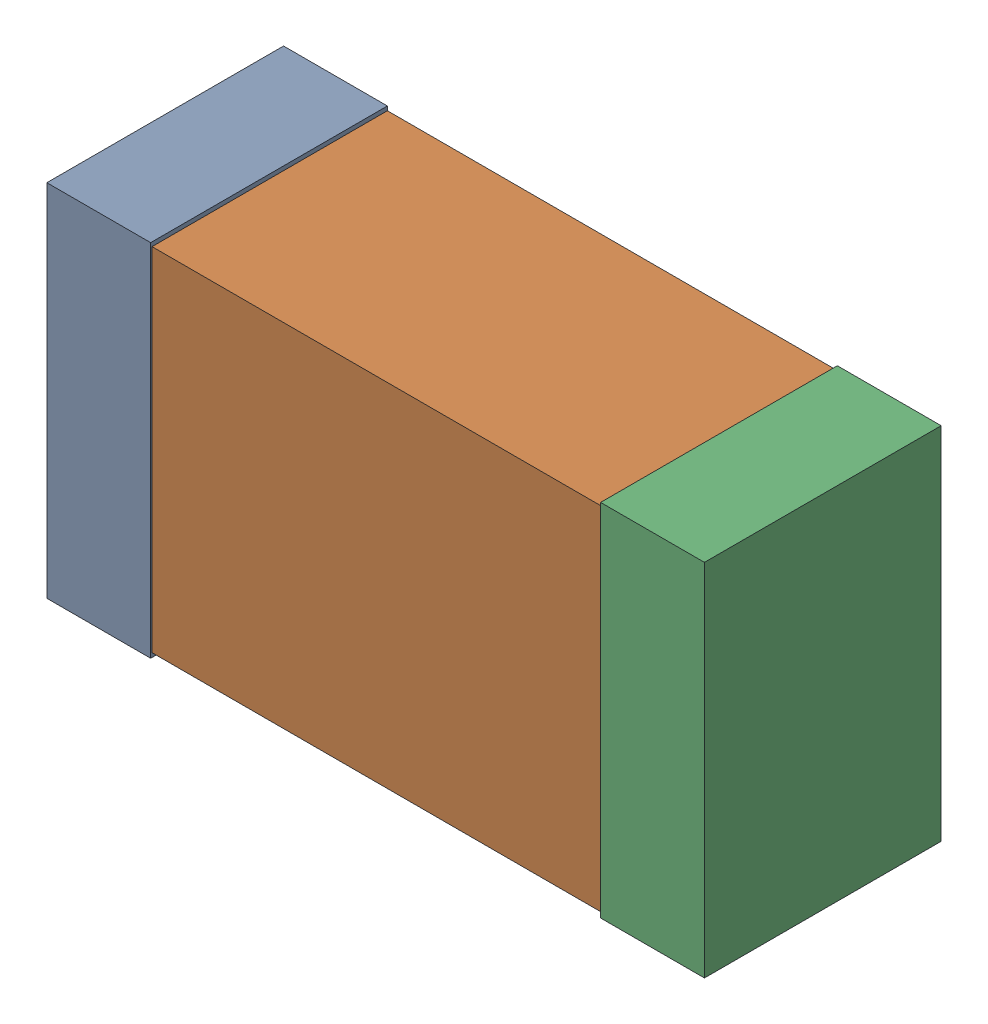
SolidWorks assembly C9_Motor_4Kanaloa_v2.0.0_Motor, configuration Default. Lengths in mm.
Overall size (2.38 1.3 0.85).
6 component instances, 2 part files, 0 mates.
Components (placement in the parent):
- 352877648-1: 352877648 [Default] at (76.74 78.232 0) size (0.38 1.3 0.85)
  - Extruded_14-1: Extruded_14 [Default] at origin size (0.38 1.3 0.85)
- 352877392-1: 352877392 [Default] at (77.74 78.232 0) size (2.2 1.27 0.85)
  - Extruded_15-1: Extruded_15 [Default] at origin size (2.2 1.27 0.85)
- 352877648-2: 352877648 [Default] at (78.74 78.232 0) size (0.38 1.3 0.85)
  - Extruded_14-1: Extruded_14 [Default] at origin size (0.38 1.3 0.85)
